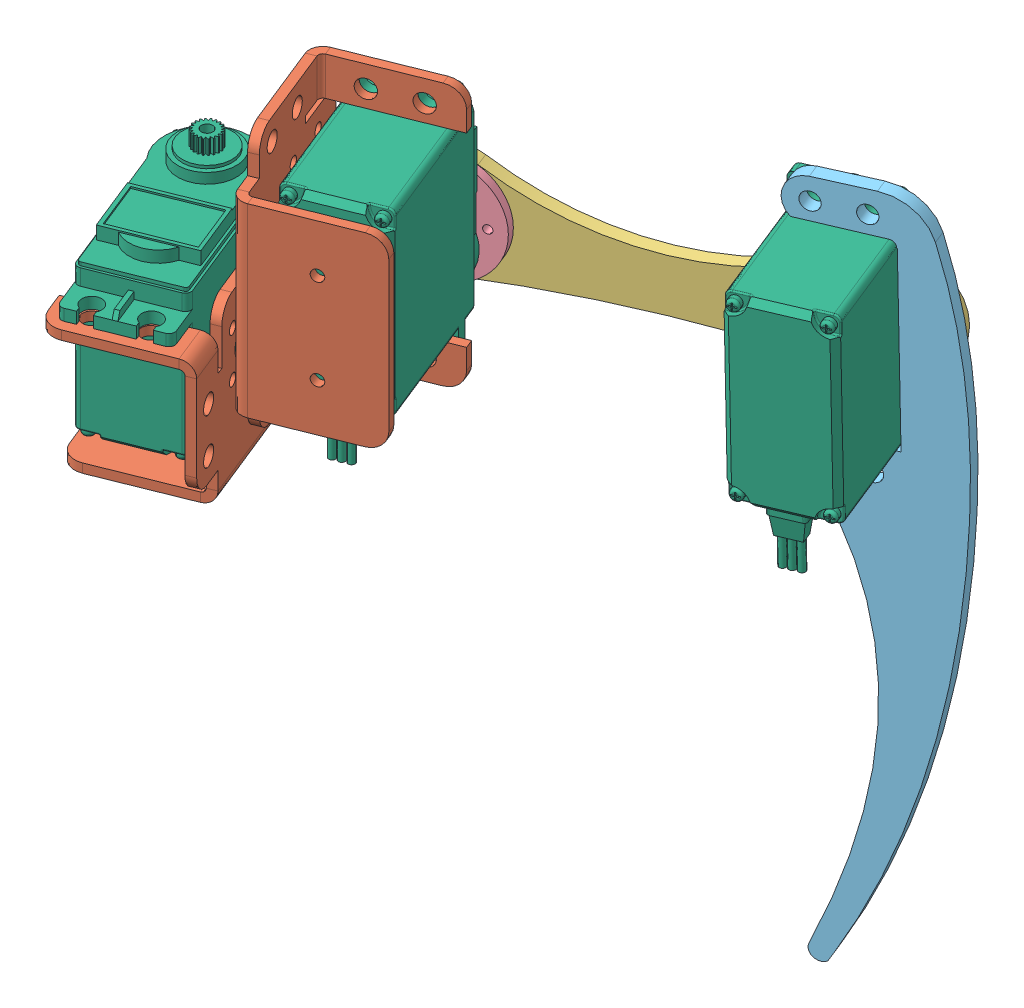
SolidWorks assembly right_leg, configuration Default. Lengths in mm.
Overall size (161.57 166.25 125.47).
10 component instances, 6 part files, 24 mates.
Components (placement in the parent):
- bearing-1: bearing [Default] at (77.3096 14.4854 59.4755) x (1 0 0) z (0 0 -1) size (9.5 4 9.5)
- coxa-1: coxa [Défaut] at (13.113 50.5854 27.2459) x (0 1 0) z (-0.372995 0 -0.927833) size (58 27 37.5)
- femur-1: femur [Default] at (-84.652 82.704 39.9918) x (0.052863 -0.267956 -0.96198) z (0.858871 -0.47926 0.180693) size (45.33 66.4 77.86)
- metal horn-1: metal horn [Default] at (105.3984 -2.9634 11.8482) x (0.006322 -0.999977 -0.002541) z (0.927812 0.006813 -0.372986) size (24 5 24)
- tibia-1: tibia [Default] at (-111.6789 34.8576 12.4602) x (-0.896671 0.226105 -0.380601) z (0.335416 -0.214112 -0.917416) size (45.21 146.32 43.03)
- coxa-2: coxa [Défaut] at (7.2383 15.3354 12.6326) x (-0.372995 0 -0.927833) z (0 1 0) size (58 27 37.5)
- servo-1: servo [Default] at (2.7396 42.3664 14.7504) x (-0.927833 0 0.372995) z (-0.372995 0 -0.927833) size (19.81 42.14 58.23)
- servo-2: servo [Default] at (26.0186 50.8724 -7.0756) x (-0.927833 0 0.372995) z (0 -1 0) size (19.81 42.14 58.23)
- servo-3: servo [Default] at (96.5608 51.5521 -35.4341) x (-0.927709 -0.016344 0.372945) z (0.015164 -0.999866 -0.006096) size (19.81 42.14 58.23)
- metal horn-2: metal horn [Default] at (34.6989 -3.4826 40.2699) x (0.006322 -0.999977 -0.002541) z (0.927812 0.006813 -0.372986) size (24 5 24)
Mates (geometry in assembly coordinates):
- Concentric2: concentric anti-aligned: cylinder of bracket-1 through (5.4573 40.8354 2.8402) axis (0.927833 0 -0.372995) radius 4; cylinder of bracket-2 through (1.746 40.8354 4.3322) axis (-0.927833 0 0.372995) radius 4
- Concentric3: concentric anti-aligned: cylinder of bracket-1 through (5.4573 47.8354 2.8402) axis (0.927833 0 -0.372995) radius 1.25; cylinder of bracket-2 through (1.746 47.8354 4.3322) axis (-0.927833 0 0.372995) radius 1.25
- Coincident2: coincident anti-aligned: plane of bracket-1 through (13.113 71.0854 27.2459) normal (-0.927833 0 0.372995); plane of bracket-2 through (-0.4081 15.3354 -6.388) normal (0.927833 0 -0.372995)
- Coincident3: coincident anti-aligned: plane of bracket-2 through (7.2383 48.3354 12.6326) normal (0 1 0); plane of hs-422_sws-1 through (-15.6426 48.3354 22.1402) normal (0 -1 0)
- Parallel1: parallel anti-aligned: plane of bracket-2 through (-2.2637 15.3354 -5.642) normal (-0.927833 0 0.372995); plane of hs-422_sws-1 through (2.7396 42.3664 14.7504) normal (0.927833 0 -0.372995)
- Concentric5: concentric aligned: cylinder of bracket-2 through (-10.2885 17.3354 8.9007) axis (0 1 0) radius 1.25; cylinder of hs-422_sws-1 through (-10.2885 54.0905 8.9007) axis (0 1 0) radius 1.27
- Concentric4: concentric aligned: cylinder of ball bearing-1 through (-10.2885 11.3354 8.9007) axis (0 1 0) radius 1.5; cylinder of bracket-2 through (-10.2885 17.3354 8.9007) axis (0 1 0) radius 1.25
- Coincident5: coincident anti-aligned: plane of ball bearing-1 through (-7.1235 15.3354 8.9007) normal (0 1 0); plane of bracket-2 through (-25.4596 15.3354 3.6828) normal (0 -1 0)
- Parallel2: parallel anti-aligned: plane of bracket-1 through (14.9687 71.0854 26.5) normal (0.927833 0 -0.372995); plane of hs-422_sws-2 through (7.6363 50.8724 0.3141) normal (-0.927833 0 0.372995)
- Coincident7: coincident anti-aligned: plane of bracket-1 through (0.8042 50.5854 -3.3726) normal (-0.372995 0 -0.927833); plane of hs-422_sws-2 through (5.4099 50.8724 -5.2241) normal (0.372995 0 0.927833)
- Concentric6: concentric aligned: cylinder of bracket-1 through (26.1639 40.5854 19.8438) axis (-0.372995 0 -0.927833) radius 1.25; cylinder of hs-422_sws-2 through (12.4544 40.5854 -14.2588) axis (-0.372995 0 -0.927833) radius 1.27
- Coincident8: coincident anti-aligned: plane of tibia-1 through (104.349 3.5618 -44.9983) normal (-0.372995 0 -0.927833); plane of hs-422_sws-3 through (75.9546 51.2283 -33.5835) normal (0.372995 0 0.927833)
- Concentric7: concentric aligned: cylinder of hs-422_sws-3 through (99.4449 75.219 -14.2824) axis (-0.372995 0 -0.927833) radius 2.1844; cylinder of tibia-1 through (89.4971 75.219 -39.0277) axis (-0.372995 0 -0.927833) radius 1.905
- Parallel3: parallel anti-aligned: plane of tibia-1 through (83.4362 31.3002 -69.276) normal (-0.927709 -0.016344 0.372945); plane of hs-422_sws-3 through (96.5608 51.5521 -35.4341) normal (0.927709 0.016344 -0.372945)
- Coincident10: coincident anti-aligned: plane of femur-1 through (61.1076 73.6024 -45.8528) normal (0.372995 0 0.927833); plane of metal horn-1 through (78.9888 41.1046 -53.0411) normal (-0.372995 0 -0.927833)
- Concentric8: concentric aligned: cylinder of femur-1 through (77.8697 41.1046 -55.8246) axis (0.372995 0 0.927833) radius 3.8735; cylinder of metal horn-1 through (78.8023 41.1046 -53.505) axis (0.372995 0 0.927833) radius 3
- Concentric9: concentric aligned: cylinder of femur-1 through (85.7562 41.1625 -58.995) axis (0.372995 0 0.927833) radius 1.2192; cylinder of metal horn-1 through (87.6212 41.1625 -54.3558) axis (0.372995 0 0.927833) radius 0.889
- Coincident11: coincident anti-aligned: plane of femur-1 through (61.1076 73.6024 -45.8528) normal (0.372995 0 0.927833); plane of metal horn-2 through (8.2893 40.5854 -24.6195) normal (-0.372995 0 -0.927833)
- Concentric10: concentric aligned: cylinder of femur-1 through (7.1705 40.5854 -27.403) axis (0.372995 0 0.927833) radius 3.8735; cylinder of metal horn-2 through (8.1029 40.5854 -25.0834) axis (0.372995 0 0.927833) radius 1.4
- Concentric11: concentric aligned: cylinder of femur-1 through (-0.716 40.5275 -24.2326) axis (0.372995 0 0.927833) radius 1.2192; cylinder of metal horn-2 through (1.1489 40.5275 -19.5934) axis (0.372995 0 0.927833) radius 0.889
- Concentric12: concentric anti-aligned: cylinder of metal horn-1 through (78.8023 41.1046 -53.505) axis (0.372995 0 0.927833) radius 1.4; cylinder of hs-422_sws-3 through (83.1539 41.1046 -42.6804) axis (-0.372995 0 -0.927833) radius 1.27
- Coincident12: coincident anti-aligned: plane of metal horn-1 through (79.5673 38.1046 -51.657) normal (0.372995 0 0.927833); plane of hs-422_sws-3 through (70.2024 51.2283 -47.8923) normal (-0.372995 0 -0.927833)
- Concentric13: concentric anti-aligned: cylinder of hs-422_sws-2 through (12.4544 40.5854 -14.2588) axis (-0.372995 0 -0.927833) radius 1.27; cylinder of metal horn-2 through (8.1029 40.5854 -25.0834) axis (0.372995 0 0.927833) radius 1.4
- Coincident13: coincident anti-aligned: plane of hs-422_sws-2 through (-0.3423 50.8724 -19.5328) normal (-0.372995 0 -0.927833); plane of metal horn-2 through (8.8678 37.5854 -23.2354) normal (0.372995 0 0.927833)
